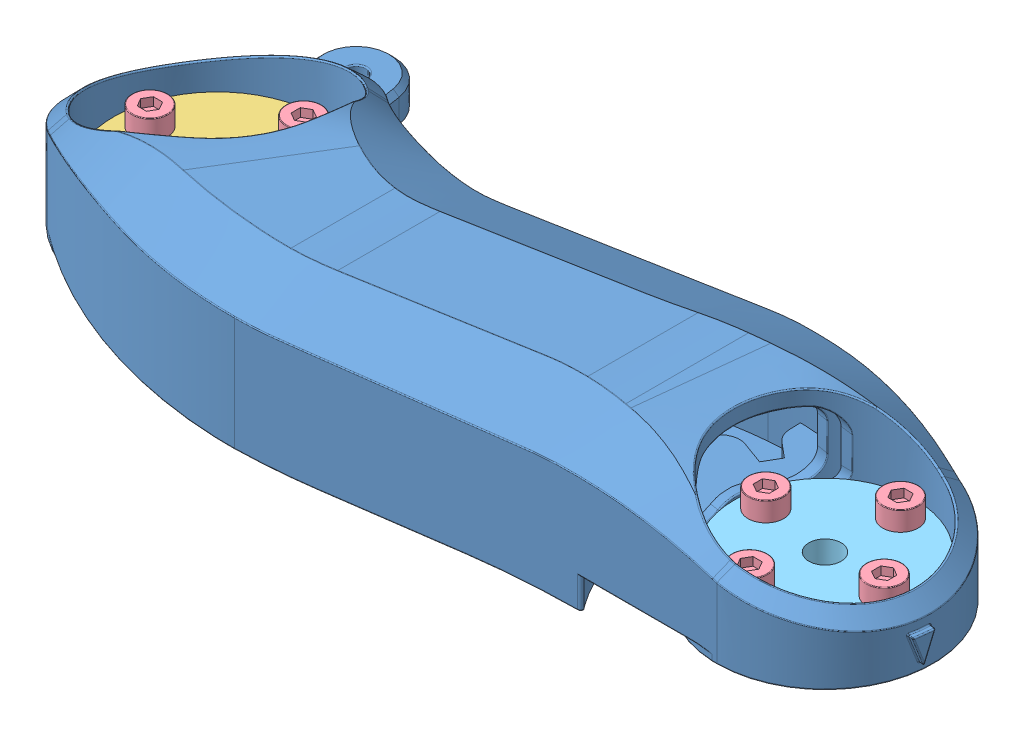
SolidWorks assembly QN1903.02大臂组件, configuration 默认. Lengths in mm.
13 component instances, 5 part files, 19 mates.
Components (placement in the parent):
- QN1903.02—01大臂-1: QN1903.02—01大臂 [默认] at origin size (149.2 33.5 71.31)
- QN1903.02—02挡块-1: QN1903.02—02挡块 [Default] at (-107.2023 4.47 -13.1019) x (0.449943 0 -0.893057) z (0 -1 0) size (16.02 8.43 10.03)
- 联轴器1-1: 联轴器1 [默认] at (-107.2026 6.51 -13.0998) x (0.12294 0 -0.992414) z (-0.992414 0 -0.12294) size (32 13 32)
- GB／T70．1-2000内六角圆柱头螺钉M3×7-1: GB／T70．1-2000内六角圆柱头螺钉M3×7 [默认] at (-105.7273 9.51 -25.0088) x (0 -1 0) z (0 0 1) size (10 5.5 5.5)
- GB／T70．1-2000内六角圆柱头螺钉M3×7-4: GB／T70．1-2000内六角圆柱头螺钉M3×7 [默认] at (-95.2936 9.51 -11.6245) x (0 -1 0) z (-1 0 0) size (10 5.5 5.5)
- GB／T70．1-2000内六角圆柱头螺钉M3×7-3: GB／T70．1-2000内六角圆柱头螺钉M3×7 [默认] at (-108.6779 9.51 -1.1908) x (0 -1 0) z (0 0 -1) size (10 5.5 5.5)
- GB／T70．1-2000内六角圆柱头螺钉M3×7-2: GB／T70．1-2000内六角圆柱头螺钉M3×7 [默认] at (-119.1116 9.51 -14.5751) x (0 -1 0) z (1 0 0) size (10 5.5 5.5)
- 联轴器2-1: 联轴器2 [默认] at (0 16.2737 0) x (-0.992782 0 -0.119933) z (-0.119933 0 0.992782) size (28 13 28)
- GB／T70．1-2000内六角圆柱头螺钉M3×7-5: GB／T70．1-2000内六角圆柱头螺钉M3×7 [默认] at (10.4242 19.2737 1.2593) x (0 -1 0) z (0 0 1) size (10 5.5 5.5)
- GB／T70．1-2000内六角圆柱头螺钉M3×7-8: GB／T70．1-2000内六角圆柱头螺钉M3×7 [默认] at (-1.2593 19.2737 10.4242) x (0 -1 0) z (-1 0 0) size (10 5.5 5.5)
- GB／T70．1-2000内六角圆柱头螺钉M3×7-7: GB／T70．1-2000内六角圆柱头螺钉M3×7 [默认] at (-10.4242 19.2737 -1.2593) x (0 -1 0) z (0 0 -1) size (10 5.5 5.5)
- GB／T70．1-2000内六角圆柱头螺钉M3×7-6: GB／T70．1-2000内六角圆柱头螺钉M3×7 [默认] at (1.2593 19.2737 -10.4242) x (0 -1 0) z (1 0 0) size (10 5.5 5.5)
- GB／T70．1-2000内六角圆柱头螺钉M3×7-9: GB／T70．1-2000内六角圆柱头螺钉M3×7 [默认] at (-84.8759 -3.53 -1.8533) x (0 1 0) z (0 0 1) size (10 5.5 5.5)
Mates (geometry in assembly coordinates):
- 重合1: coincident aligned: plane of QN1903.02—01大臂-1 through (0 0 0) normal (0 0 1); plane of assembly through (0 0 0) normal (0 0 1)
- 重合2: coincident aligned: plane of QN1903.02—01大臂-1 through (0 0 0) normal (0 1 0); plane of assembly through (0 0 0) normal (0 1 0)
- 重合3: coincident aligned: plane of QN1903.02—01大臂-1 through (0 0 0) normal (1 0 0); plane of assembly through (0 0 0) normal (1 0 0)
- 重合4: coincident anti-aligned: plane of QN1903.02—01大臂-1 through (-131.5099 3.51 -31.8679) normal (0 1 0); plane of 联轴器1-1 through (-107.2026 3.51 -13.0998) normal (0 -1 0)
- 同心1: concentric anti-aligned: cylinder of QN1903.02—01大臂-1 through (-107.2026 26.8612 -13.0998) axis (0 -1 0) radius 8.2559; cylinder of 联轴器1-1 through (-107.2026 -6.49 -13.0998) axis (0 1 0) radius 8
- 同心4: concentric aligned: cylinder of QN1903.02—01大臂-1 through (-105.7273 26.8612 -25.0088) axis (0 -1 0) radius 1.5; cylinder of 联轴器1-1 through (-105.7273 13.51 -25.0088) axis (0 -1 0) radius 2
- 同心5: concentric aligned: cylinder of QN1903.02—01大臂-1 through (-119.1116 26.8612 -14.5751) axis (0 -1 0) radius 1.5; cylinder of 联轴器1-1 through (-119.1116 13.51 -14.5751) axis (0 -1 0) radius 2
- 重合5: coincident anti-aligned: plane of 联轴器1-1 through (-107.2026 6.51 -13.0998) normal (0 1 0); plane of GB／T70．1-2000内六角圆柱头螺钉M3×7-1 through (-102.9773 6.51 -25.0088) normal (0 -1 0)
- 同心6: concentric anti-aligned: cylinder of 联轴器1-1 through (-105.7273 13.51 -25.0088) axis (0 -1 0) radius 2; cylinder of GB／T70．1-2000内六角圆柱头螺钉M3×7-1 through (-105.7273 9.51 -25.0088) axis (0 1 0) radius 2.75
- 重合6: coincident anti-aligned: plane of QN1903.02—01大臂-1 through (-23.4971 13.2737 61.62) normal (0 1 0); plane of 联轴器2-1 through (0 13.2737 0) normal (0 -1 0)
- 同心7: concentric anti-aligned: cylinder of QN1903.02—01大臂-1 through (0 34.4869 0) axis (0 -1 0) radius 7.5; cylinder of 联轴器2-1 through (0 3.2737 0) axis (0 1 0) radius 7.5
- 同心10: concentric aligned: cylinder of QN1903.02—01大臂-1 through (1.2593 34.4869 -10.4242) axis (0 -1 0) radius 1.5; cylinder of 联轴器2-1 through (1.2593 23.2737 -10.4242) axis (0 -1 0) radius 1.5
- 重合7: coincident anti-aligned: plane of 联轴器2-1 through (0 16.2737 0) normal (0 1 0); plane of GB／T70．1-2000内六角圆柱头螺钉M3×7-5 through (13.1742 16.2737 1.2593) normal (0 -1 0)
- 同心11: concentric anti-aligned: cylinder of 联轴器2-1 through (10.4242 23.2737 1.2593) axis (0 -1 0) radius 1.5; cylinder of GB／T70．1-2000内六角圆柱头螺钉M3×7-5 through (10.4242 19.2737 1.2593) axis (0 1 0) radius 2.75
- 同心12: concentric anti-aligned: cylinder of QN1903.02—01大臂-1 through (-84.8759 6.9041 -1.8533) axis (0 -1 0) radius 1.2; cylinder of QN1903.02—02挡块-1 through (-84.8759 -12.03 -1.8533) axis (0 1 0) radius 1.25
- 重合8: coincident anti-aligned: plane of QN1903.02—01大臂-1 through (-78.263 2.47 -8.0845) normal (0 -1 0); plane of QN1903.02—02挡块-1 through (-84.8759 2.47 -1.8533) normal (0 1 0)
- 同心13: concentric aligned: cylinder of QN1903.02—01大臂-1 through (-107.2023 28.73 -13.1019) axis (0 -1 0) radius 18.7561; cylinder of QN1903.02—02挡块-1 through (-107.2023 4.47 -13.1019) axis (0 -1 0) radius 21.5
- 重合9: coincident anti-aligned: plane of QN1903.02—02挡块-1 through (-84.8759 -0.53 -1.8533) normal (0 -1 0); plane of GB／T70．1-2000内六角圆柱头螺钉M3×7-9 through (-87.6259 -0.53 -1.8533) normal (0 1 0)
- 同心14: concentric anti-aligned: cylinder of QN1903.02—02挡块-1 through (-84.8759 -12.03 -1.8533) axis (0 1 0) radius 1.25; cylinder of GB／T70．1-2000内六角圆柱头螺钉M3×7-9 through (-84.8759 -3.53 -1.8533) axis (0 -1 0) radius 2.75
